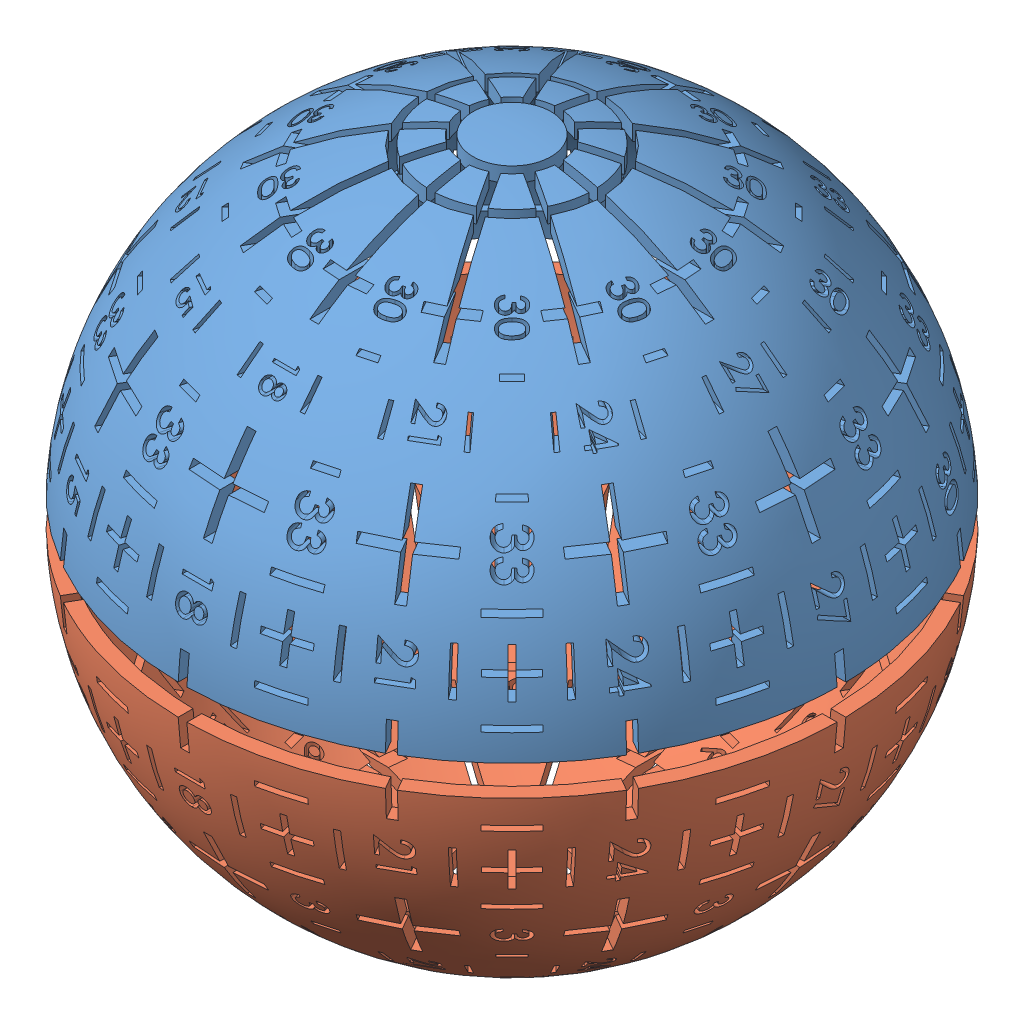
SolidWorks assembly BlackColored_Balls, configuration Default. Lengths in mm.
Overall size (121.29 88.9 121.29).
2 component instances, 2 part files, 3 mates.
Components (placement in the parent):
- BlackBallV2_TopColored-1: BlackBallV2_TopColored [Default] at (-21.5448 -32.4159 17.5791) size (88.79 42.35 88.79)
- BlackBallV2_BottomColored-1: BlackBallV2_BottomColored [Default] at (-21.5448 -32.3159 17.5791) x (0.5 0 -0.866025) z (-0.866025 0 -0.5) size (88.79 42.35 88.79)
Mates (geometry in assembly coordinates):
- Concentric1: concentric: circle of BlackBallV2_TopColored-1; circle of BlackBallV2_BottomColored-1
- Distance2: distance = 4.1 mm: plane of BlackBallV2_BottomColored-1 through (-21.5448 -34.4159 17.5791) normal (0 1 0); plane of BlackBallV2_TopColored-1 through (-21.5448 -30.3159 17.5791) normal (0 -1 0)
- Coincident4: coincident: plane of BlackBallV2_TopColored-1 through (17.2435 -26.5639 -4.1377) normal (-0.5 0 -0.866025); plane of BlackBallV2_BottomColored-1 through (17.2435 -38.1678 -4.1377) normal (-0.5 0 -0.866025)
